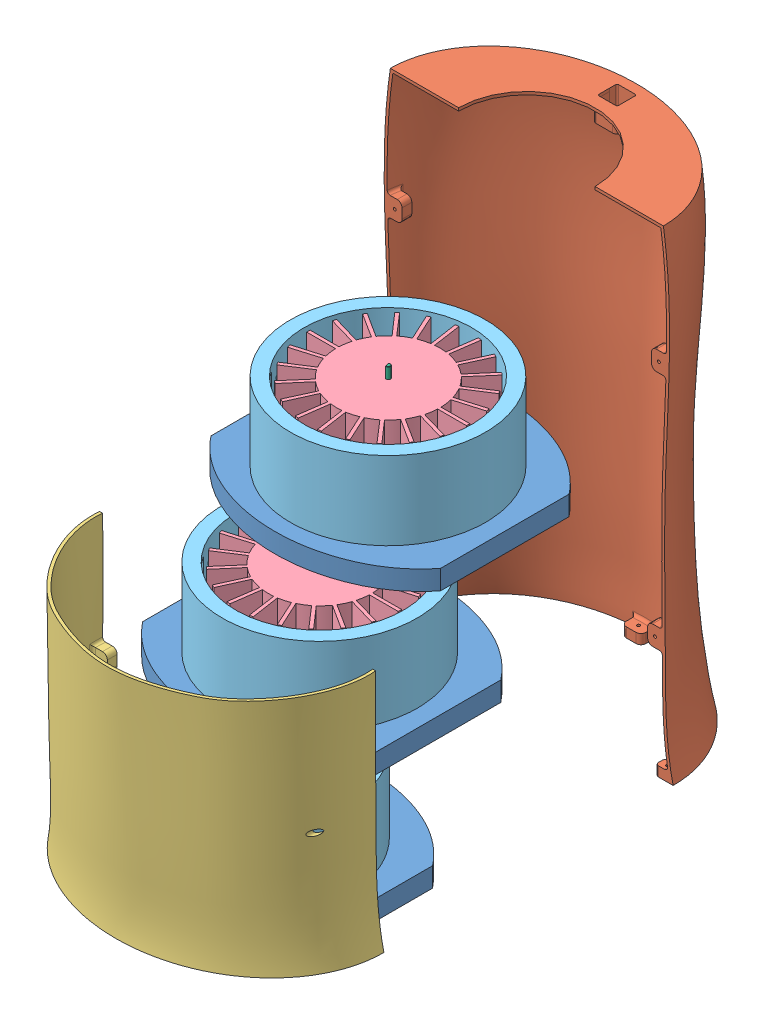
SolidWorks assembly first_prototype, configuration Default. Lengths in mm.
Overall size (382.4 494.92 576.72).
21 component instances, 8 part files, 19 mates.
Components (placement in the parent):
- dispenserHolder-2: dispenserHolder [Default] at (185.6922 42.5602 523.1559) x (0 0 -1) z (1 0 0) size (235.97 20.02 235.4)
- BASE_UPPER_FRONT-1: BASE_UPPER_FRONT [Default] at (185.5423 153.5602 240.5566) x (-1 0 0) z (0 0 -1) size (382.4 494.92 145.32)
- BASE_UPPER_BACK_BOT-1: BASE_UPPER_BACK_BOT [Default] at (185.5423 153.5602 537.1874) x (-1 0 0) z (0 0 -1) size (374.5 255.63 159.69)
- dispenserHolder-3: dispenserHolder [Default] at (185.6922 172.5602 453.1559) x (0 0 -1) z (1 0 0) size (235.97 20.02 235.4)
- dispenserHolder-4: dispenserHolder [Default] at (185.6922 302.5602 383.1559) x (0 0 -1) z (1 0 0) size (235.97 20.02 235.4)
- AssemSwash-1: AssemSwash [Default] at (476.3356 29.4543 460.9076) x (0.281885 0 0.959448) z (-0.959448 0 0.281885) size (200 99.6 200)
  - pillStorage_NEW-1: pillStorage_NEW [Default] at (-22.7041 55.2059 296.4042) size (165 46 165)
  - pilldispenserbase-1: pilldispenserbase [Default] at (-22.2041 13.2059 296.4042) size (200 90.1 200)
  - Nema17-2: Nema17 [Predeterminado] at (-22.7041 51.2059 296.4042) size (42.3 64.5 47.8)
  - RC522-1: RC522 [Default] at (-22.2041 58.0459 389.4042) x (1 0 0) z (0 -1 0) size (39.2 15.3 59.9)
- AssemSwash-2: AssemSwash [Default] at (476.3356 159.4543 390.9076) x (0.281885 0 0.959448) z (-0.959448 0 0.281885) size (200 99.6 200)
  - pillStorage_NEW-1: pillStorage_NEW [Default] at (-22.7041 55.2059 296.4042) size (165 46 165)
  - pilldispenserbase-1: pilldispenserbase [Default] at (-22.2041 13.2059 296.4042) size (200 90.1 200)
  - Nema17-2: Nema17 [Predeterminado] at (-22.7041 51.2059 296.4042) size (42.3 64.5 47.8)
  - RC522-1: RC522 [Default] at (-22.2041 58.0459 389.4042) x (1 0 0) z (0 -1 0) size (39.2 15.3 59.9)
- AssemSwash-3: AssemSwash [Default] at (476.3356 289.4543 320.9076) x (0.281885 0 0.959448) z (-0.959448 0 0.281885) size (200 99.6 200)
  - pillStorage_NEW-1: pillStorage_NEW [Default] at (-22.7041 55.2059 296.4042) size (165 46 165)
  - pilldispenserbase-1: pilldispenserbase [Default] at (-22.2041 13.2059 296.4042) size (200 90.1 200)
  - Nema17-2: Nema17 [Predeterminado] at (-22.7041 51.2059 296.4042) size (42.3 64.5 47.8)
  - RC522-1: RC522 [Default] at (-22.2041 58.0459 389.4042) x (1 0 0) z (0 -1 0) size (39.2 15.3 59.9)
- BASE_UPPER_BACK_TOP-1: BASE_UPPER_BACK_TOP [Default] at (185.2686 151.9398 538.3181) x (-1 0 0) z (0 0 -1) size (344.81 254.19 270.47) (hidden)
Mates (geometry in assembly coordinates):
- Concentric5: concentric anti-aligned: cylinder of BASE_UPPER_FRONT-1 through (54.4723 155.5602 230.5566) axis (0 0 1) radius 1.5; cylinder of BASE_UPPER_BACK_BOT-1 through (54.472 155.5602 547.1874) axis (0 0 -1) radius 1.5
- Concentric6: concentric anti-aligned: cylinder of BASE_UPPER_FRONT-1 through (316.9121 155.5602 230.5566) axis (0 0 1) radius 1.5; cylinder of BASE_UPPER_BACK_BOT-1 through (316.9121 155.5602 547.1874) axis (0 0 -1) radius 1.5
- Parallel2: parallel aligned: plane of BASE_UPPER_FRONT-1 through (185.5423 524.5602 240.5566) normal (0 1 0); plane of BASE_UPPER_BACK_BOT-1 through (185.5423 278.5602 537.1874) normal (0 1 0)
- Coincident8: coincident aligned: plane of dispenserHolder-2 through (185.6922 32.5602 523.1559) normal (0 -1 0); plane of BASE_UPPER_BACK_BOT-1 through (185.5423 32.5602 537.1874) normal (0 -1 0)
- Coincident9: coincident aligned: plane of dispenserHolder-2 through (303.3802 32.5502 586.8438) normal (1 0 0); plane of dispenserHolder-3 through (303.3802 162.5502 516.8438) normal (1 0 0)
- Coincident10: coincident aligned: plane of dispenserHolder-3 through (303.3802 162.5502 516.8438) normal (1 0 0); plane of dispenserHolder-4 through (303.3802 292.5502 446.8438) normal (1 0 0)
- Distance2: distance = 120 mm anti-aligned: plane of dispenserHolder-4 through (185.6922 292.5602 383.1559) normal (0 -1 0); plane of dispenserHolder-3 through (185.6922 172.5602 453.1559) normal (0 1 0)
- Distance3: distance = 120 mm anti-aligned: plane of dispenserHolder-2 through (185.6922 42.5602 523.1559) normal (0 1 0); plane of dispenserHolder-3 through (185.6922 162.5602 453.1559) normal (0 -1 0)
- LimitDistance3: limit distance = 70 mm: line of dispenserHolder-4 through (68.0042 292.5602 446.9333) axis (0 1 0); line of dispenserHolder-3 through (68.0042 162.5602 516.9333) axis (0 1 0)
- LimitDistance4: limit distance = 70 mm: line of dispenserHolder-2 through (68.0042 32.5602 586.9333) axis (0 1 0); line of dispenserHolder-3 through (68.0042 162.5602 516.9333) axis (0 1 0)
- Width1: width anti-aligned: plane of BASE_UPPER_FRONT-1 through (61.9723 155.5602 230.5566) normal (1 0 0); plane of BASE_UPPER_FRONT-1 through (309.4121 155.5602 230.5566) normal (-1 0 0); plane of dispenserHolder-3 through (68.0042 162.5502 516.9333) normal (-1 0 0); plane of dispenserHolder-3 through (303.3802 162.5502 516.8438) normal (1 0 0)
- Concentric7: concentric aligned: cylinder of dispenserHolder-2 through (185.6922 52.5602 523.1559) axis (0 -1 0) radius 100; cylinder of AssemSwash-1/pilldispenserbase-1 through (185.6922 132.6602 523.1559) axis (0 -1 0) radius 100
- Coincident11: coincident anti-aligned: plane of dispenserHolder-2 through (185.6922 42.5602 523.1559) normal (0 1 0); plane of AssemSwash-1/pilldispenserbase-1 through (185.6922 42.5602 523.1559) normal (0 -1 0)
- Coincident12: coincident anti-aligned: plane of dispenserHolder-3 through (185.6922 172.5602 453.1559) normal (0 1 0); plane of AssemSwash-2/pilldispenserbase-1 through (185.6922 172.5602 453.1559) normal (0 -1 0)
- Coincident13: coincident anti-aligned: plane of dispenserHolder-4 through (185.6922 302.5602 383.1559) normal (0 1 0); plane of AssemSwash-3/pilldispenserbase-1 through (185.6922 302.5602 383.1559) normal (0 -1 0)
- Concentric8: concentric aligned: cylinder of dispenserHolder-4 through (185.6922 312.5602 383.1559) axis (0 -1 0) radius 100; cylinder of AssemSwash-3/pilldispenserbase-1 through (185.6922 392.6602 383.1559) axis (0 -1 0) radius 100
- Concentric9: concentric aligned: cylinder of dispenserHolder-3 through (185.6922 182.5602 453.1559) axis (0 -1 0) radius 100; cylinder of AssemSwash-2/pilldispenserbase-1 through (185.6922 262.6602 453.1559) axis (0 -1 0) radius 100
- Lock1: lock: unknown of dispenserHolder-2; unknown of BASE_UPPER_BACK_BOT-1
- Lock2: lock: unknown of BASE_UPPER_BACK_BOT-1; unknown of BASE_UPPER_BACK_TOP-1
